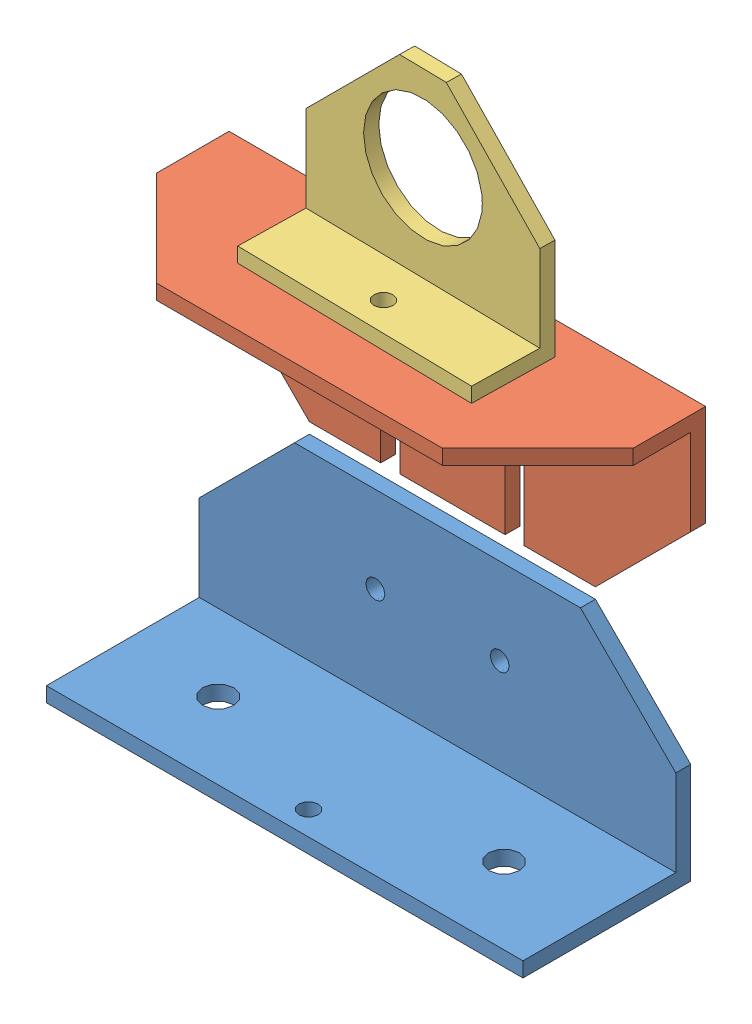
SolidWorks assembly Sup_Divisor de feixe, configuration Default. Lengths in mm.
Overall size (100 125.92 41.32).
10 component instances, 6 part files, 18 mates.
Components (placement in the parent):
- Base do divisor-1: Base do divisor [Default] at (-56.6739 2.9025 27.9341) size (100 41.23 35.2)
- Base do divisor B-1: Base do divisor B [Default] at (43.3261 81.3513 24.8091) x (-1 0 0) z (0 0 1) size (100 41.23 35.2)
- Suporte do Divisor-1: Suporte do Divisor [Default] at (-32.1193 87.6013 30.6764) x (0.999823 0 0.018792) z (-0.018792 0 0.999823) size (50 41.23 17.19)
- Parafuso Padrao M4 16-1: Parafuso Padrao M4 16 [Default] at (6.3761 22.9025 -10.3889) x (1 0 0) z (0 1 0) size (8 13 8) (hidden)
- Parafuso Padrao M4 16-2: Parafuso Padrao M4 16 [Default] at (-19.7239 22.9025 -10.3889) x (0.998184 -0.06024 0) z (0.06024 0.998184 0) size (8 13 8) (hidden)
- Parafuso Padrao M4 16-3: Parafuso Padrao M4 16 [Default] at (-6.6739 87.6013 7.2101) x (0.93764 0 0.347608) z (-0.347608 0 0.93764) size (8 13 8) (hidden)
- Porca M4-1: Porca M4 [Default] at (-19.7239 22.9025 -4.1389) x (1 0 0) z (0 -1 0) size (7.78 3.12 8.95) (hidden)
- Porca M4-2: Porca M4 [Default] at (6.3761 22.9025 -1.0139) x (1 0 0) z (0 1 0) size (7.78 3.12 8.95) (hidden)
- Porca M4-3: Porca M4 [Default] at (-6.6739 78.2263 7.2101) x (0.202843 0 0.979211) z (-0.979211 0 0.202843) size (7.78 3.12 8.95) (hidden)
- Divisor de feixe-1: Divisor de feixe [Default] at (-6.4647 107.6013 -3.9206) x (0.999823 0.000014 0.018792) z (-0.018792 0 0.999823) size (25.4 25.4 3) (hidden)
Mates (geometry in assembly coordinates):
- Coincident1: coincident anti-aligned: plane of Base do divisor-1 through (43.3261 2.9025 -7.2639) normal (0 0 -1); plane of Base do divisor B-1 through (-56.6739 81.3513 -7.2639) normal (0 0 1)
- Coincident2: coincident anti-aligned: plane of Base do divisor B-1 through (-56.6739 84.4763 24.8091) normal (0 1 0); plane of Suporte do Divisor-1 through (17.8718 84.4763 31.616) normal (0 -1 0)
- Concentric4: concentric aligned: circle of Suporte do Divisor-1; cylinder of Parafuso Padrao M4 16-3 through (-6.6739 77.6013 7.2101) axis (0 1 0) radius 2
- Coincident4: coincident anti-aligned: plane of Suporte do Divisor-1 through (17.8718 87.6013 31.616) normal (0 1 0); plane of Parafuso Padrao M4 16-3 through (-6.6739 87.6013 7.2101) normal (0 -1 0)
- Concentric5: concentric aligned: cylinder of Base do divisor-1 through (6.3761 22.9025 27.9341) axis (0 0 -1) radius 2; cylinder of Parafuso Padrao M4 16-1 through (6.3761 22.9025 -0.3889) axis (0 0 -1) radius 2
- Concentric7: concentric anti-aligned: cylinder of Parafuso Padrao M4 16-1 through (6.3761 22.9025 -0.3889) axis (0 0 -1) radius 2; cylinder of Porca M4-2 through (6.3761 22.9025 -4.1389) axis (0 0 1) radius 2
- Coincident7: coincident anti-aligned: plane of Base do divisor-1 through (43.3261 2.9025 -4.1389) normal (0 0 1); plane of Porca M4-2 through (10.2665 25.1129 -4.1389) normal (0 0 -1)
- Coincident9: coincident: plane of Base do divisor-1 through (43.3261 2.9025 -4.1389) normal (0 0 1); line of Porca M4-1 through (-19.693 18.4281 -4.1389) axis (0.862553 0.505967 0)
- Concentric9: concentric aligned: cylinder of Parafuso Padrao M4 16-3 through (-6.6739 77.6013 7.2101) axis (0 1 0) radius 2; circle of Porca M4-3
- Coincident11: coincident anti-aligned: plane of Base do divisor B-1 through (-56.6739 81.3513 24.8091) normal (0 -1 0); plane of Porca M4-3 through (-8.0492 81.3513 11.468) normal (0 1 0)
- Concentric10: concentric aligned: cylinder of Suporte do Divisor-1 through (-7.1238 107.6013 31.1462) axis (0.018792 0 -0.999823) radius 12.7; cylinder of Divisor de feixe-1 through (-6.521 107.6013 -0.9211) axis (0.018792 0 -0.999823) radius 12.7
- Coincident12: coincident aligned: plane of Suporte do Divisor-1 through (18.4745 87.6013 -0.4513) normal (-0.018792 0 0.999823); plane of Divisor de feixe-1 through (-6.521 107.6013 -0.9211) normal (-0.018792 0 0.999823)
- Concentric11: concentric aligned: cylinder of Base do divisor B-1 through (-6.6739 43.2513 7.2101) axis (0 1 0) radius 2; cylinder of Parafuso Padrao M4 16-3 through (-6.6739 77.6013 7.2101) axis (0 1 0) radius 2
- Concentric12: concentric aligned: circle of Base do divisor-1; cylinder of Parafuso Padrao M4 16-2 through (-19.7239 22.9025 -0.3889) axis (0 0 -1) radius 2
- Parallel1: parallel aligned: plane of Parafuso Padrao M4 16-1 through (6.3761 22.9025 -13.3889) normal (0 0 -1); plane of Parafuso Padrao M4 16-2 through (-19.7239 22.9025 -13.3889) normal (0 0 -1)
- Tangent3: tangent anti-aligned: plane of Base do divisor B-1 through (-21.7239 43.2513 24.8091) normal (1 0 0); cylinder of Parafuso Padrao M4 16-2 through (-19.7239 22.9025 -0.3889) axis (0 0 -1) radius 2
- Tangent4: tangent anti-aligned: plane of Base do divisor B-1 through (4.3761 61.3513 24.8091) normal (1 0 0); cylinder of Parafuso Padrao M4 16-1 through (6.3761 22.9025 -0.3889) axis (0 0 -1) radius 2
- Concentric13: concentric aligned: cylinder of Parafuso Padrao M4 16-2 through (-19.7239 22.9025 -0.3889) axis (0 0 -1) radius 2; cylinder of Porca M4-1 through (-19.7239 22.9025 -1.0139) axis (0 0 -1) radius 2
